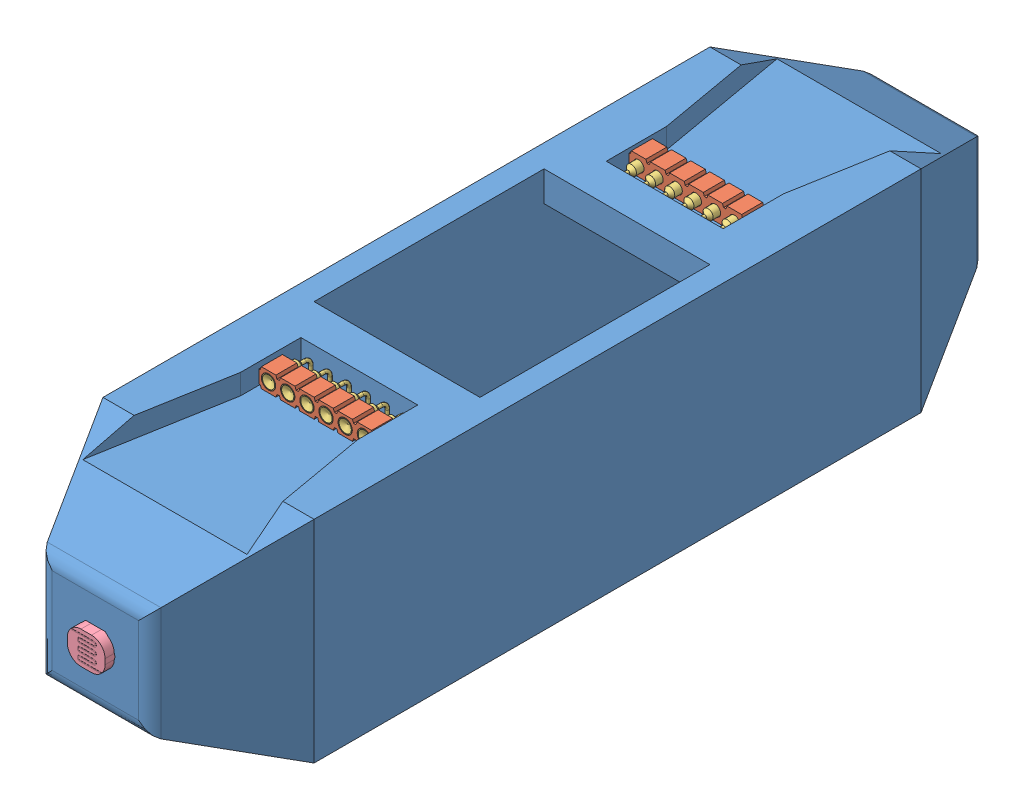
SolidWorks assembly Module_LDR, configuration Default. Lengths in mm.
Overall size (28 28 112.98).
19 component instances, 4 part files, 14 mates.
Components (placement in the parent):
- Module - RB_Gears-1: Module - RB_Gears [LDR] at (37.8746 66.7149 80.4494) size (28 28 110.5)
- mill-max-399-10-106-10-007000-1: mill-max-399-10-106-10-007000 [Default] at (87.4391 79.2849 107.5811) x (1 0 0) z (0 -1 0) size (15.24 5.81 5.74)
  - mill-max-399-10-106-10-007000_P3XX-11-010-00-000000(P306-11-010-00-000000)-1: mill-max-399-10-106-10-007000_P3XX-11-010-00-000000(P306-11-010-00-000000) [Default] at (-56.7488 -1.0694 1.27) size (15.24 2.79 2.54)
  - mill-max-399-10-106-10-007000_1960(1960-0-00-15-00-00-03-0)-1: mill-max-399-10-106-10-007000_1960(1960-0-00-15-00-00-03-0) [Default] at (-50.7044 -1.0694 0) x (0 -1 0) z (1 0 0) size (5.81 5.38 1.83)
  - mill-max-399-10-106-10-007000_1960(1960-0-00-15-00-00-03-0)-2: mill-max-399-10-106-10-007000_1960(1960-0-00-15-00-00-03-0) [Default] at (-43.0844 -1.0694 0) x (0 -1 0) z (1 0 0) size (5.81 5.38 1.83)
  - mill-max-399-10-106-10-007000_1960(1960-0-00-15-00-00-03-0)-3: mill-max-399-10-106-10-007000_1960(1960-0-00-15-00-00-03-0) [Default] at (-55.7844 -1.0694 0) x (0 -1 0) z (1 0 0) size (5.81 5.38 1.83)
  - mill-max-399-10-106-10-007000_1960(1960-0-00-15-00-00-03-0)-4: mill-max-399-10-106-10-007000_1960(1960-0-00-15-00-00-03-0) [Default] at (-48.1644 -1.0694 0) x (0 -1 0) z (1 0 0) size (5.81 5.38 1.83)
  - mill-max-399-10-106-10-007000_1960(1960-0-00-15-00-00-03-0)-5: mill-max-399-10-106-10-007000_1960(1960-0-00-15-00-00-03-0) [Default] at (-53.2444 -1.0694 0) x (0 -1 0) z (1 0 0) size (5.81 5.38 1.83)
  - mill-max-399-10-106-10-007000_1960(1960-0-00-15-00-00-03-0)-6: mill-max-399-10-106-10-007000_1960(1960-0-00-15-00-00-03-0) [Default] at (-45.6244 -1.0694 0) x (0 -1 0) z (1 0 0) size (5.81 5.38 1.83)
- mill-max-399-10-106-10-007000-2: mill-max-399-10-106-10-007000 [Default] at (-11.6898 79.2849 53.3178) x (-1 0 0) z (0 -1 0) size (15.24 5.81 5.74)
  - mill-max-399-10-106-10-007000_P3XX-11-010-00-000000(P306-11-010-00-000000)-1: mill-max-399-10-106-10-007000_P3XX-11-010-00-000000(P306-11-010-00-000000) [Default] at (-56.7488 -1.0694 1.27) size (15.24 2.79 2.54)
  - mill-max-399-10-106-10-007000_1960(1960-0-00-15-00-00-03-0)-1: mill-max-399-10-106-10-007000_1960(1960-0-00-15-00-00-03-0) [Default] at (-50.7044 -1.0694 0) x (0 -1 0) z (1 0 0) size (5.81 5.38 1.83)
  - mill-max-399-10-106-10-007000_1960(1960-0-00-15-00-00-03-0)-2: mill-max-399-10-106-10-007000_1960(1960-0-00-15-00-00-03-0) [Default] at (-43.0844 -1.0694 0) x (0 -1 0) z (1 0 0) size (5.81 5.38 1.83)
  - mill-max-399-10-106-10-007000_1960(1960-0-00-15-00-00-03-0)-3: mill-max-399-10-106-10-007000_1960(1960-0-00-15-00-00-03-0) [Default] at (-55.7844 -1.0694 0) x (0 -1 0) z (1 0 0) size (5.81 5.38 1.83)
  - mill-max-399-10-106-10-007000_1960(1960-0-00-15-00-00-03-0)-4: mill-max-399-10-106-10-007000_1960(1960-0-00-15-00-00-03-0) [Default] at (-48.1644 -1.0694 0) x (0 -1 0) z (1 0 0) size (5.81 5.38 1.83)
  - mill-max-399-10-106-10-007000_1960(1960-0-00-15-00-00-03-0)-5: mill-max-399-10-106-10-007000_1960(1960-0-00-15-00-00-03-0) [Default] at (-53.2444 -1.0694 0) x (0 -1 0) z (1 0 0) size (5.81 5.38 1.83)
  - mill-max-399-10-106-10-007000_1960(1960-0-00-15-00-00-03-0)-6: mill-max-399-10-106-10-007000_1960(1960-0-00-15-00-00-03-0) [Default] at (-45.6244 -1.0694 0) x (0 -1 0) z (1 0 0) size (5.81 5.38 1.83)
- LDR-1: LDR [Default] at (43.5733 63.3579 134.6994) size (5 4.3 4.74)
- LDR-2: LDR [Default] at (32.176 63.3579 26.1994) x (-1 0 0) z (0 0 -1) size (5 4.3 4.74)
Mates (geometry in assembly coordinates):
- Tangent1: tangent anti-aligned: plane of Module - RB_Gears-1 through (45.6246 78.0149 100.6994) normal (0 0 1); cylinder of mill-max-399-10-106-10-007000-1/mill-max-399-10-106-10-007000_1960(1960-0-00-15-00-00-03-0)-2 through (44.3546 84.5216 100.928) axis (0 1 0) radius 0.2286
- Tangent2: tangent anti-aligned: plane of Module - RB_Gears-1 through (45.6246 78.0149 100.6994) normal (0 0 1); cylinder of mill-max-399-10-106-10-007000-1/mill-max-399-10-106-10-007000_1960(1960-0-00-15-00-00-03-0)-3 through (31.6546 84.5216 100.928) axis (0 1 0) radius 0.2286
- Tangent3: tangent anti-aligned: plane of Module - RB_Gears-1 through (45.6246 78.0149 60.1994) normal (0 0 -1); cylinder of mill-max-399-10-106-10-007000-2/mill-max-399-10-106-10-007000_1960(1960-0-00-15-00-00-03-0)-2 through (31.3946 84.5216 59.9708) axis (0 1 0) radius 0.2286
- Tangent4: tangent anti-aligned: plane of Module - RB_Gears-1 through (45.6246 78.0149 60.1994) normal (0 0 -1); cylinder of mill-max-399-10-106-10-007000-2/mill-max-399-10-106-10-007000_1960(1960-0-00-15-00-00-03-0)-3 through (44.0946 84.5216 59.9708) axis (0 1 0) radius 0.2286
- Coincident3: coincident anti-aligned: plane of Module - RB_Gears-1 through (37.8746 78.0149 80.4494) normal (0 1 0); plane of mill-max-399-10-106-10-007000-2/mill-max-399-10-106-10-007000_P3XX-11-010-00-000000(P306-11-010-00-000000)-1 through (45.059 78.0149 57.1811) normal (0 -1 0)
- Coincident4: coincident anti-aligned: plane of Module - RB_Gears-1 through (37.8746 78.0149 80.4494) normal (0 1 0); plane of mill-max-399-10-106-10-007000-1/mill-max-399-10-106-10-007000_P3XX-11-010-00-000000(P306-11-010-00-000000)-1 through (30.6903 78.0149 103.7177) normal (0 -1 0)
- Coincident5: coincident anti-aligned: plane of Module - RB_Gears-1 through (45.6246 78.0149 120.6994) normal (-1 0 0); plane of mill-max-399-10-106-10-007000-1/mill-max-399-10-106-10-007000_P3XX-11-010-00-000000(P306-11-010-00-000000)-1 through (45.6246 80.1549 103.7177) normal (1 0 0)
- Coincident7: coincident anti-aligned: plane of Module - RB_Gears-1 through (30.1246 78.0149 40.1994) normal (1 0 0); plane of mill-max-399-10-106-10-007000-2/mill-max-399-10-106-10-007000_P3XX-11-010-00-000000(P306-11-010-00-000000)-1 through (30.1246 80.1549 57.1811) normal (-1 0 0)
- Concentric5: concentric aligned: cylinder of Module - RB_Gears-1 through (36.2496 66.7149 80.4484) axis (0 0 1) radius 0.5; cylinder of LDR-1 through (36.2496 66.7149 132.1994) axis (0 0 1) radius 0.25
- Concentric6: concentric aligned: cylinder of Module - RB_Gears-1 through (39.4996 66.7149 80.4484) axis (0 0 1) radius 0.5; cylinder of LDR-1 through (39.4996 66.7149 132.1994) axis (0 0 1) radius 0.25
- Coincident8: coincident anti-aligned: plane of Module - RB_Gears-1 through (37.8746 66.7149 134.6994) normal (0 0 1); plane of LDR-1 through (37.1746 67.0649 134.6994) normal (0 0 -1)
- Concentric7: concentric aligned: cylinder of Module - RB_Gears-1 through (36.2496 66.7149 80.4504) axis (0 0 -1) radius 0.5; cylinder of LDR-2 through (36.2496 66.7149 28.6994) axis (0 0 -1) radius 0.25
- Concentric8: concentric aligned: cylinder of Module - RB_Gears-1 through (39.4996 66.7149 80.4504) axis (0 0 -1) radius 0.5; cylinder of LDR-2 through (39.4996 66.7149 28.6994) axis (0 0 -1) radius 0.25
- Coincident9: coincident anti-aligned: plane of Module - RB_Gears-1 through (37.8746 66.7149 26.1994) normal (0 0 -1); plane of LDR-2 through (38.5746 67.0649 26.1994) normal (0 0 1)
